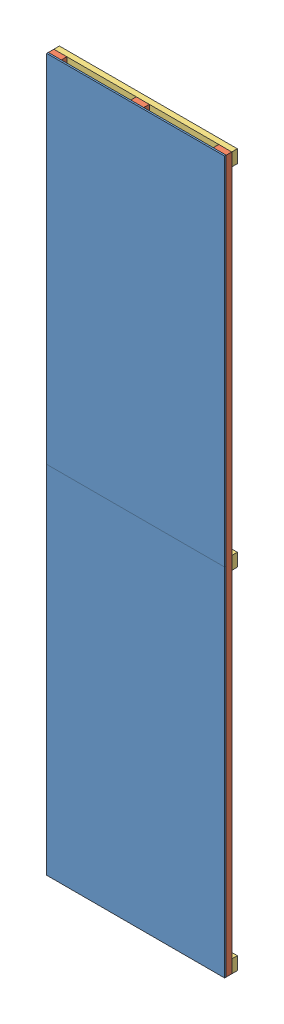
SolidWorks assembly Shelf, configuration Default. Lengths in mm.
Overall size (1219.2 4876.8 89.81).
29 component instances, 4 part files, 18 mates.
Components (placement in the parent):
- Plywood_7-16X4ftX8ft-1: Plywood_7-16X4ftX8ft [Default] at (-1214.3269 -1248.9803 333.7822) size (1219.2 2438.4 11.11)
- Plywood_7-16X4ftX8ft-2: Plywood_7-16X4ftX8ft [Default] at (-1214.3269 1189.4197 333.7822) size (1219.2 2438.4 11.11)
- 2x4x16ft-4: 2x4x16ft [Default] at (-84.0269 -1248.9803 333.7822) x (1 0 0) z (0 1 0) size (88.9 38.1 4876.8)
- 2x4x16ft-5: 2x4x16ft [Default] at (-649.1769 -1248.9803 333.7822) x (1 0 0) z (0 1 0) size (88.9 38.1 4876.8)
- 2x4x16ft-6: 2x4x16ft [Default] at (-1214.3269 -1248.9803 333.7822) x (1 0 0) z (0 1 0) size (88.9 38.1 4876.8)
- Fastened2x4x4ft-1: Fastened2x4x4ft [Default] at (-567.3467 -1138.8169 272.6519) x (0 1 0) z (-1 0 0) size (88.9 72.35 1219.2)
  - 2x4x4ft-1: 2x4x4ft [Default] at (-110.1634 -23.0303 -572.2198) size (88.9 38.1 1219.2)
  - DrywallScrew-1: DrywallScrew [Default] at (-65.7134 15.0697 624.7552) x (1 0 0) z (0 -1 0) size (6.35 6.35 72.35)
  - DrywallScrew-2: DrywallScrew [Default] at (-65.7134 15.0697 580.3052) x (1 0 0) z (0 -1 0) size (6.35 6.35 72.35)
  - DrywallScrew-3: DrywallScrew [Default] at (-65.7134 15.0697 59.6052) x (1 0 0) z (0 -1 0) size (6.35 6.35 72.35)
  - DrywallScrew-4: DrywallScrew [Default] at (-65.7134 15.0697 15.1552) x (1 0 0) z (0 -1 0) size (6.35 6.35 72.35)
  - DrywallScrew-5: DrywallScrew [Default] at (-65.7134 15.0697 -549.9948) x (1 0 0) z (0 -1 0) size (6.35 6.35 72.35)
  - DrywallScrew-6: DrywallScrew [Default] at (-65.7134 15.0697 -505.5448) x (1 0 0) z (0 -1 0) size (6.35 6.35 72.35)
- Fastened2x4x4ft-2: Fastened2x4x4ft [Default] at (-567.3467 1255.1331 272.6519) x (0 1 0) z (-1 0 0) size (88.9 72.35 1219.2)
  - 2x4x4ft-1: 2x4x4ft [Default] at (-110.1634 -23.0303 -572.2198) size (88.9 38.1 1219.2)
  - DrywallScrew-1: DrywallScrew [Default] at (-65.7134 15.0697 624.7552) x (1 0 0) z (0 -1 0) size (6.35 6.35 72.35)
  - DrywallScrew-2: DrywallScrew [Default] at (-65.7134 15.0697 580.3052) x (1 0 0) z (0 -1 0) size (6.35 6.35 72.35)
  - DrywallScrew-3: DrywallScrew [Default] at (-65.7134 15.0697 59.6052) x (1 0 0) z (0 -1 0) size (6.35 6.35 72.35)
  - DrywallScrew-4: DrywallScrew [Default] at (-65.7134 15.0697 15.1552) x (1 0 0) z (0 -1 0) size (6.35 6.35 72.35)
  - DrywallScrew-5: DrywallScrew [Default] at (-65.7134 15.0697 -549.9948) x (1 0 0) z (0 -1 0) size (6.35 6.35 72.35)
  - DrywallScrew-6: DrywallScrew [Default] at (-65.7134 15.0697 -505.5448) x (1 0 0) z (0 -1 0) size (6.35 6.35 72.35)
- Fastened2x4x4ft-3: Fastened2x4x4ft [Default] at (-642.1071 3517.6563 272.6519) x (0 -1 0) z (1 0 0) size (88.9 72.35 1219.2)
  - 2x4x4ft-1: 2x4x4ft [Default] at (-110.1634 -23.0303 -572.2198) size (88.9 38.1 1219.2)
  - DrywallScrew-1: DrywallScrew [Default] at (-65.7134 15.0697 624.7552) x (1 0 0) z (0 -1 0) size (6.35 6.35 72.35)
  - DrywallScrew-2: DrywallScrew [Default] at (-65.7134 15.0697 580.3052) x (1 0 0) z (0 -1 0) size (6.35 6.35 72.35)
  - DrywallScrew-3: DrywallScrew [Default] at (-65.7134 15.0697 59.6052) x (1 0 0) z (0 -1 0) size (6.35 6.35 72.35)
  - DrywallScrew-4: DrywallScrew [Default] at (-65.7134 15.0697 15.1552) x (1 0 0) z (0 -1 0) size (6.35 6.35 72.35)
  - DrywallScrew-5: DrywallScrew [Default] at (-65.7134 15.0697 -549.9948) x (1 0 0) z (0 -1 0) size (6.35 6.35 72.35)
  - DrywallScrew-6: DrywallScrew [Default] at (-65.7134 15.0697 -505.5448) x (1 0 0) z (0 -1 0) size (6.35 6.35 72.35)
Mates (geometry in assembly coordinates):
- Coincident1: coincident anti-aligned: plane of Plywood_7-16X4ftX8ft-1 through (-1214.3269 1189.4197 344.8947) normal (0 1 0); plane of Plywood_7-16X4ftX8ft-2 through (-1214.3269 1189.4197 344.8947) normal (0 -1 0)
- Coincident2: coincident aligned: plane of Plywood_7-16X4ftX8ft-1 through (-1214.3269 -1248.9803 344.8947) normal (0 0 1); plane of Plywood_7-16X4ftX8ft-2 through (-1214.3269 1189.4197 344.8947) normal (0 0 1)
- Coincident3: coincident aligned: plane of Plywood_7-16X4ftX8ft-1 through (4.8731 -1248.9803 344.8947) normal (1 0 0); plane of Plywood_7-16X4ftX8ft-2 through (4.8731 1189.4197 344.8947) normal (1 0 0)
- Coincident4: coincident anti-aligned: plane of Plywood_7-16X4ftX8ft-1 through (-1214.3269 -1248.9803 333.7822) normal (0 0 -1); plane of 2x4x16ft-4 through (-84.0269 3627.8197 333.7822) normal (0 0 1)
- Coincident6: coincident anti-aligned: plane of Plywood_7-16X4ftX8ft-1 through (-1214.3269 -1248.9803 333.7822) normal (0 0 -1); plane of 2x4x16ft-5 through (-649.1769 3627.8197 333.7822) normal (0 0 1)
- Coincident7: coincident anti-aligned: plane of Plywood_7-16X4ftX8ft-1 through (-1214.3269 -1248.9803 333.7822) normal (0 0 -1); plane of 2x4x16ft-6 through (-1214.3269 3627.8197 333.7822) normal (0 0 1)
- Coincident8: coincident aligned: plane of Plywood_7-16X4ftX8ft-1 through (-1214.3269 -1248.9803 344.8947) normal (0 -1 0); plane of 2x4x16ft-4 through (-84.0269 -1248.9803 333.7822) normal (0 -1 0)
- Coincident9: coincident aligned: plane of Plywood_7-16X4ftX8ft-1 through (-1214.3269 -1248.9803 344.8947) normal (0 -1 0); plane of 2x4x16ft-5 through (-649.1769 -1248.9803 333.7822) normal (0 -1 0)
- Coincident10: coincident aligned: plane of Plywood_7-16X4ftX8ft-1 through (-1214.3269 -1248.9803 344.8947) normal (0 -1 0); plane of 2x4x16ft-6 through (-1214.3269 -1248.9803 333.7822) normal (0 -1 0)
- Coincident11: coincident: moEndPointRef_w of Plywood_7-16X4ftX8ft-1; moEndPointRef_w of 2x4x16ft-5
- Coincident12: coincident aligned: plane of Plywood_7-16X4ftX8ft-1 through (4.8731 -1248.9803 344.8947) normal (1 0 0); plane of 2x4x16ft-4 through (4.8731 3627.8197 333.7822) normal (1 0 0)
- Coincident13: coincident aligned: plane of Plywood_7-16X4ftX8ft-1 through (-1214.3269 -1248.9803 344.8947) normal (-1 0 0); plane of 2x4x16ft-6 through (-1214.3269 3627.8197 333.7822) normal (-1 0 0)
- Coincident27: coincident anti-aligned: circle of 2x4x16ft-4; circle of Fastened2x4x4ft-1/2x4x4ft-1
- Coincident28: coincident aligned: plane of 2x4x16ft-4 through (4.8731 3627.8197 333.7822) normal (1 0 0); plane of Fastened2x4x4ft-1/2x4x4ft-1 through (4.8731 -1248.9803 295.6822) normal (1 0 0)
- Coincident29: coincident anti-aligned: circle of 2x4x16ft-4; circle of Fastened2x4x4ft-2/2x4x4ft-1
- Coincident30: coincident aligned: plane of 2x4x16ft-4 through (4.8731 3627.8197 333.7822) normal (1 0 0); plane of Fastened2x4x4ft-2/2x4x4ft-1 through (4.8731 1144.9697 295.6822) normal (1 0 0)
- Coincident32: coincident anti-aligned: circle of 2x4x16ft-4; circle of Fastened2x4x4ft-3/2x4x4ft-1
- Coincident33: coincident aligned: plane of 2x4x16ft-4 through (4.8731 3627.8197 333.7822) normal (1 0 0); plane of Fastened2x4x4ft-3/2x4x4ft-1 through (4.8731 3627.8197 295.6822) normal (1 0 0)
